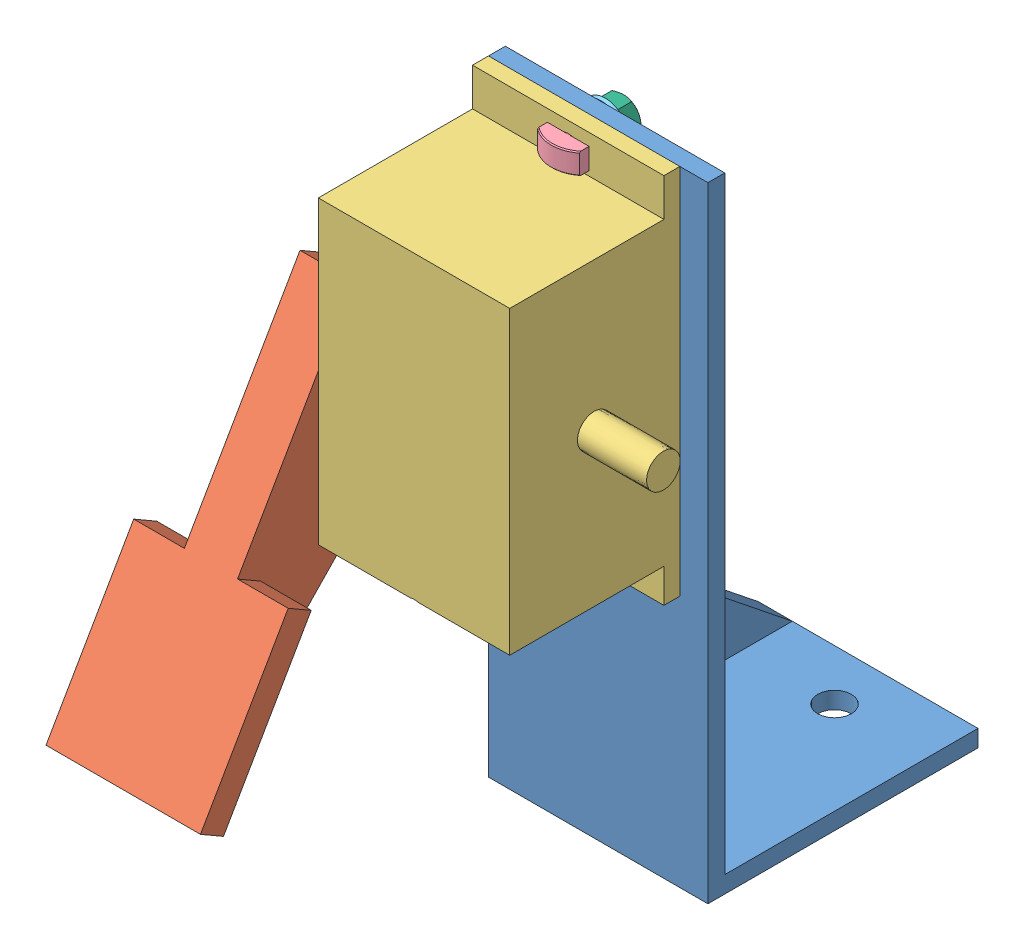
SolidWorks assembly EA4, configuration Default. Lengths in mm.
Overall size (143.05 262.66 260.65).
10 component instances, 6 part files, 19 mates.
Components (placement in the parent):
- EB5-1: EB5 [Default] at (-114.2478 -116.3037 -29.843) size (82.55 234.95 101.6)
- EA3-1: EA3 [Default] at (-6.3794 -155.1404 121.9178) x (-1 0 0) z (0 0.866025 -0.5) size (143.05 125.43 222.11)
  - EB4_2-1: EB4_2 [Default] at (50.3684 86.3483 116.5793) size (58.1 38.1 153)
  - EB4_1-1: EB4_1 [Default] at (-27.6316 86.3483 185.4593) x (0 0.5 0.866025) z (1 0 0) size (140 64 124)
- t-head bolt_ai-1: t-head bolt_ai [TBOLT 0.3125-18x0.875x0.875-N] at (-14.7478 110.1463 84.107) x (0 0 -1) z (0 -1 0) size (28.57 15.67 7.94)
- t-head bolt_ai-2: t-head bolt_ai [TBOLT 0.3125-18x0.875x0.875-N] at (-14.7478 -17.1037 84.107) x (0 0 -1) z (0 -1 0) size (28.57 15.67 7.94)
- flat washer type a narrow_ai-1: flat washer type a narrow_ai [Preferred Narrow FW 0.3125] at (-14.7478 -17.1037 63.756) x (0 0 -1) z (0.923728 0.383049 0) size (1.65 17.48 17.48)
- flat washer type a narrow_ai-2: flat washer type a narrow_ai [Preferred Narrow FW 0.3125] at (-14.7478 110.1463 63.756) x (0 0 -1) z (0.923728 0.383049 0) size (1.65 17.48 17.48)
- hex nut_ai-1: hex nut_ai [HNUT 0.3125-18-D-N] at (-14.7478 110.1463 63.756) x (0.866025 -0.5 0) z (0 0 1) size (12.7 14.66 6.93)
- hex nut_ai-2: hex nut_ai [HNUT 0.3125-18-D-N] at (-14.7478 -17.1037 63.756) x (0.866025 -0.5 0) z (0 0 1) size (12.7 14.66 6.93)
Mates (geometry in assembly coordinates):
- Coincident6: coincident: plane of EB5-1 through (31.8022 -116.3037 71.757) normal (0 0 1); plane of EA3-1/EB4_1-1 through (-50.7478 -7.8438 71.757) normal (0 0 -1)
- Coincident7: coincident: line of EB5-1 through (31.8022 118.6463 71.757) axis (-1 0 0); line of EA3-1/EB4_1-1 through (-50.7478 118.6463 71.757) axis (1 0 0)
- Coincident8: coincident: line of EB5-1 through (-50.7478 -116.3037 71.757) axis (0 1 0); line of EA3-1/EB4_1-1 through (-50.7478 118.6463 71.757) axis (0 -1 0)
- Concentric4: concentric: cylinder of EA3-1/EB4_1-1 through (-14.7478 110.1463 135.757) axis (0 0 -1) radius 4.25; cylinder of t-head bolt_ai-1 through (-14.7478 110.1463 84.107) axis (0 0 1) radius 3.9688
- Parallel3: parallel: line of EA3-1/EB4_1-1 through (-50.7478 118.6463 77.757) axis (1 0 0); line of t-head bolt_ai-1 through (-6.9119 114.115 77.757) axis (-1 0 0)
- Coincident11: coincident: plane of EA3-1/EB4_1-1 through (-50.7478 118.6463 77.757) normal (0 0 1); plane of t-head bolt_ai-1 through (-6.9119 106.1775 77.757) normal (0 0 -1)
- Concentric5: concentric: cylinder of EB5-1 through (-14.7478 -17.1037 -29.843) axis (0 0 1) radius 4.25; cylinder of t-head bolt_ai-2 through (-14.7478 -17.1037 84.107) axis (0 0 1) radius 3.9688
- Parallel4: parallel: line of EA3-1/EB4_1-1 through (-10.2478 -21.3537 77.757) axis (1 0 0); line of t-head bolt_ai-2 through (-6.9119 -13.135 77.757) axis (-1 0 0)
- Coincident13: coincident: plane of EA3-1/EB4_1-1 through (-50.7478 -21.3537 77.757) normal (0 0 1); plane of t-head bolt_ai-2 through (-6.9119 -21.0725 77.757) normal (0 0 -1)
- Concentric6: concentric: cylinder of t-head bolt_ai-1 through (-14.7478 110.1463 84.107) axis (0 0 1) radius 3.9688; cylinder of flat washer type a narrow_ai-2 through (-14.7478 110.1463 98.681) axis (0 0 1) radius 4.3688
- Coincident14: coincident: plane of EB5-1 through (31.8022 -109.9537 65.407) normal (0 0 -1); plane of flat washer type a narrow_ai-2 through (-18.0948 118.2174 65.407) normal (0 0 1)
- Concentric7: concentric: cylinder of t-head bolt_ai-2 through (-14.7478 -17.1037 84.107) axis (0 0 1) radius 3.9688; cylinder of flat washer type a narrow_ai-1 through (-14.7478 -17.1037 98.681) axis (0 0 1) radius 4.3688
- Coincident15: coincident: plane of EB5-1 through (31.8022 -109.9537 65.407) normal (0 0 -1); plane of flat washer type a narrow_ai-1 through (-18.0948 -9.0326 65.407) normal (0 0 1)
- Concentric8: concentric: cylinder of t-head bolt_ai-1 through (-14.7478 110.1463 84.107) axis (0 0 1) radius 3.9688; cylinder of hex nut_ai-1 through (-14.7478 110.1463 56.8218) axis (0 0 1) radius 3.2639
- Coincident16: coincident: plane of flat washer type a narrow_ai-2 through (-16.4213 114.1819 63.756) normal (0 0 -1); plane of hex nut_ai-1 through (-11.0817 116.4963 63.756) normal (0 0 1)
- Parallel5: parallel: plane of EB5-1 through (31.8022 118.6463 71.757) normal (0 1 0); plane of hex nut_ai-1 through (-11.0817 116.4963 56.8218) normal (0 1 0)
- Concentric9: concentric: cylinder of t-head bolt_ai-2 through (-14.7478 -17.1037 84.107) axis (0 0 1) radius 3.9688; cylinder of hex nut_ai-2 through (-14.7478 -17.1037 56.8218) axis (0 0 1) radius 3.2639
- Coincident18: coincident: plane of flat washer type a narrow_ai-1 through (-16.4213 -13.0681 63.756) normal (0 0 -1); plane of hex nut_ai-2 through (-11.0817 -10.7537 63.756) normal (0 0 1)
- Parallel6: parallel: plane of EB5-1 through (31.8022 118.6463 71.757) normal (0 1 0); plane of hex nut_ai-2 through (-11.0817 -10.7537 56.8218) normal (0 1 0)
